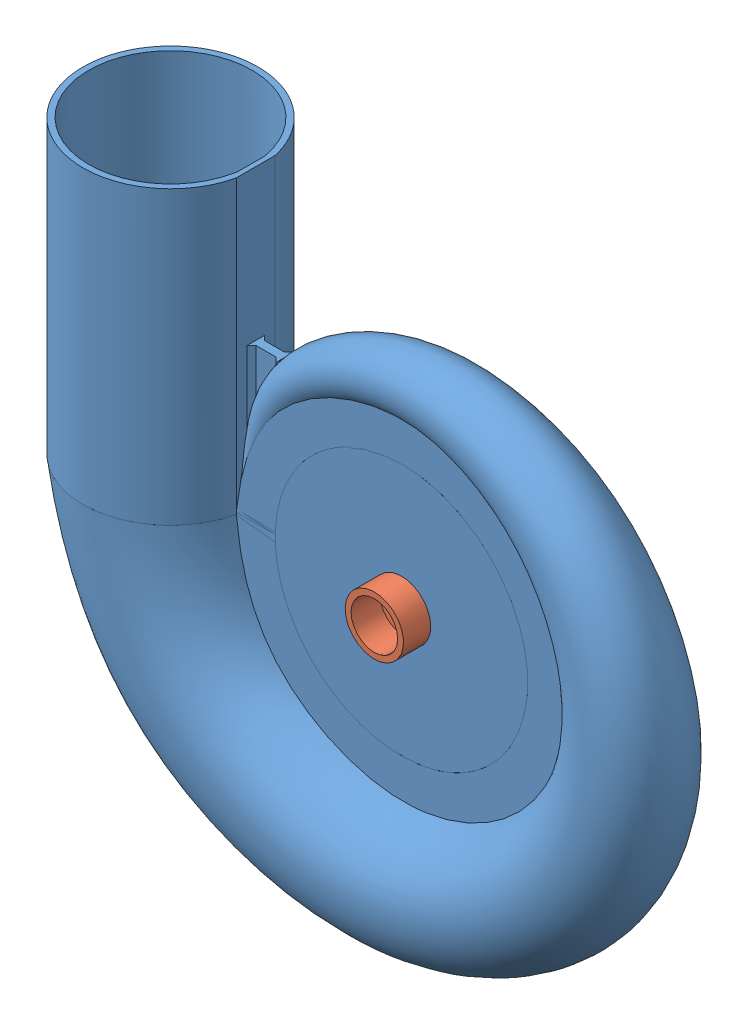
SolidWorks assembly compressorModel, configuration Default. Lengths in mm.
Overall size (321.54 321.04 100.08).
4 component instances, 4 part files, 7 mates.
Components (placement in the parent):
- housing-1: housing [Default] at (12.935 175.4007 312.2345) size (321.54 321.04 90.15)
- impeller-1: impeller [Default] at (12.935 175.4007 321.2345) x (0.268632 0.963243 0) z (-0.963243 0.268632 0) size (130 76.44 130)
- cover-1: cover [Default] at (12.935 175.4007 302.2345) x (0 1 0) z (0 0 1) size (140 140 45)
- rotatingAMI-1: rotatingAMI [Default] at (12.935 175.4007 319.2345) x (1 0 0) z (0 1 0) size (139 50 139)
Mates (geometry in assembly coordinates):
- Coincident1: coincident anti-aligned: plane of impeller-1 through (12.935 175.4007 321.2345) normal (0 0 1); plane of housing-1 through (12.935 175.4007 321.2345) normal (0 0 -1)
- Concentric1: concentric anti-aligned: cylinder of housing-1 through (12.935 175.4007 321.2345) axis (0 0 1) radius 15; cylinder of impeller-1 through (12.935 175.4007 259.7984) axis (0 0 -1) radius 15
- Coincident3: coincident anti-aligned: plane of housing-1 through (-52.065 175.4007 302.2345) normal (0 0 -1); plane of cover-1 through (-52.065 175.4007 302.2345) normal (0 0 1)
- Coincident4: coincident anti-aligned: plane of housing-1 through (81.435 175.4007 297.2345) normal (1 0 0); plane of cover-1 through (81.435 172.9007 292.2345) normal (-1 0 0)
- Coincident5: coincident anti-aligned: plane of housing-1 through (-52.065 172.9007 297.2345) normal (0 -1 0); plane of cover-1 through (81.435 172.9007 292.2345) normal (0 1 0)
- Coincident6: coincident anti-aligned: plane of impeller-1 through (12.935 175.4007 319.2345) normal (0 0 -1); plane of rotatingAMI-1 through (12.935 175.4007 319.2345) normal (0 0 1)
- Coincident7: coincident anti-aligned: line of housing-1 through (12.935 175.4007 422.2345) axis (0 0 -1); line of rotatingAMI-1 through (12.935 175.4007 269.2345) axis (0 0 1)
